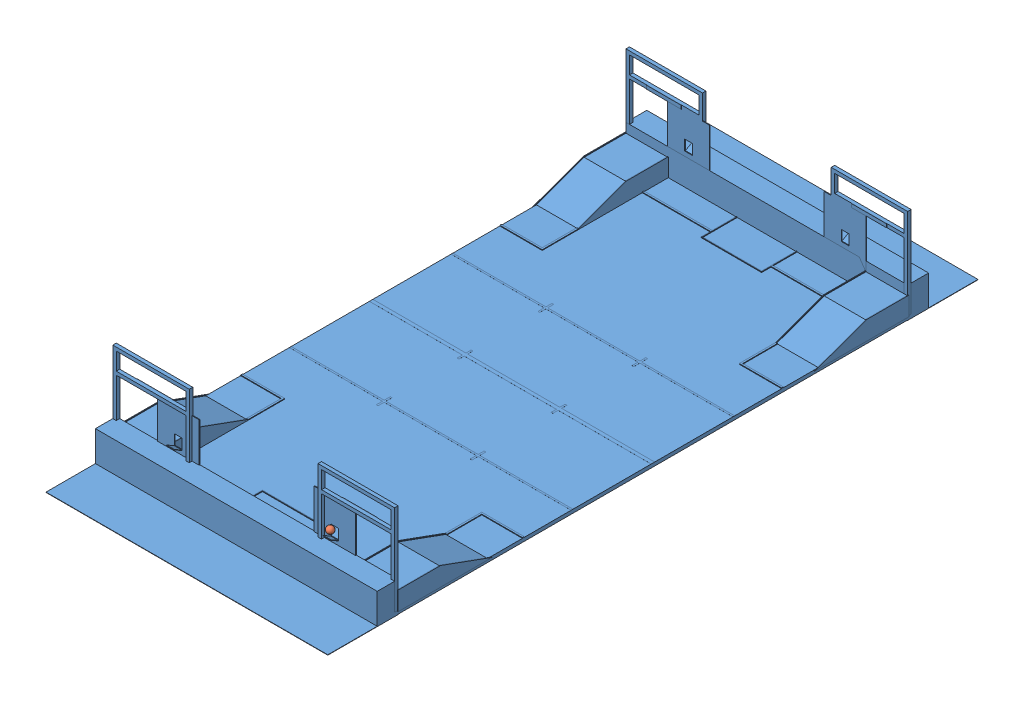
SolidWorks assembly Assem1, configuration Default. Lengths in mm.
Overall size (8136 2710 18688.65).
2 component instances, 2 part files, 0 mates.
Components (placement in the parent):
- field-1: field [Default] at (6400.7746 8839.1366 14423.5293) size (8136 2710 18688.65)
- Ball2-1: Ball2 [Default] at (8658.9457 9927.633 21906.9023) size (200 200 200)
